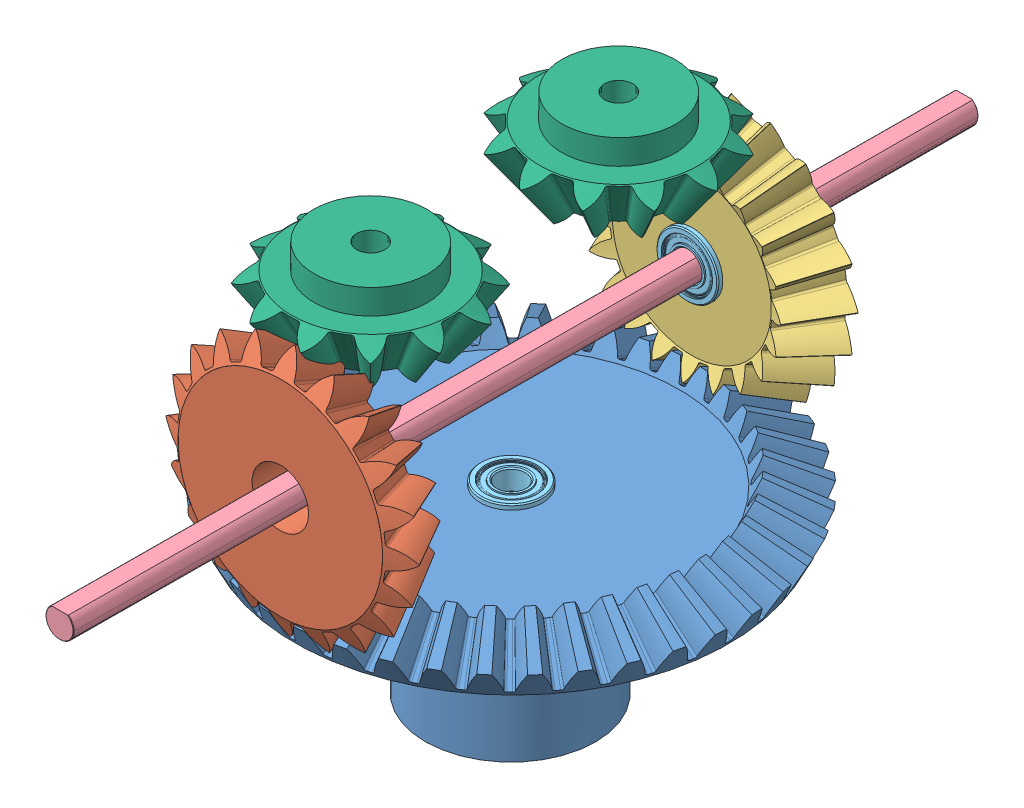
SolidWorks assembly ARMUS-200-000, configuration Default. Lengths in mm.
Overall size (118.35 104.13 203.23).
9 component instances, 6 part files, 21 mates.
Components (placement in the parent):
- ARMUS-200-001-9: ARMUS-200-001 [ARMUS-200-001] x (0 0.999978 -0.006651) z (0.161152 -0.006564 -0.986908) size (45.52 103.08 103.08)
- ARMUS-200-002-1: ARMUS-200-002 [ARMUS-200-002] at (0 30.1556 51.826) x (0 -0.006651 -0.999978) z (-0.715158 -0.698947 0.004649) size (14.5 56.42 56.42)
- straight bevel pinion_ai-2: straight bevel pinion_ai [Inch - Straight bevel pinion 10DP20PT 40GT 20PA 0.5FW ---20O3.0H2.0MD0.5N] at (0 29.4636 -52.2224) x (0 0.006651 0.999978) z (0.702579 0.71159 -0.004733) size (14.5 56.42 56.42)
- ARMUS-200-003.step-1: ARMUS-200-003.step [Default] at (0 29.1339 -101.7959) x (0 -0.999978 0.006651) z (-1 0 0) size (5.71 203.2 6.34)
- ARMUS-200-004.step-1: ARMUS-200-004.step [Default] at (0 3.0335 -0.0202) x (-0.573566 -0.005448 -0.819141) z (0.819159 -0.003815 -0.573553) size (13.87 4.75 13.87)
- ARMUS-200-004.step-2: ARMUS-200-004.step [Default] at (0 29.5168 -44.2216) x (-0.995747 -0.09213 0.000613) z (-0.092132 0.995725 -0.006623) size (13.87 4.75 13.87)
- ARMUS-200-004.step-3: ARMUS-200-004.step [Default] at (0 30.1024 43.8252) x (0.337758 0.941212 -0.00626) z (-0.941233 0.33775 -0.002246) size (13.87 4.75 13.87)
- straight bevel gear_ai-7: straight bevel gear_ai [ARMUS-200-005] at (-4.8298 60.7194 -28.969) x (0 -0.999978 0.006651) z (-0.258 0.006426 0.966124) size (18.93 43.65 43.65)
- straight bevel gear_ai-8: straight bevel gear_ai [ARMUS-200-005] at (-3.8808 60.3841 27.6811) x (0 -0.999978 0.006651) z (-1 0 0) size (18.93 43.65 43.65)
Mates (geometry in assembly coordinates):
- Coincident1: coincident anti-aligned: plane of ARMUS-200-001-9
- Coincident2: coincident: point of ARMUS-200-001-9; point of ARMUS-200-002-1
- Perpendicular1: perpendicular: line of ARMUS-200-001-9 through (0 -9.9998 0.0665) axis (0 0.999978 -0.006651); line of ARMUS-200-002-1 through (0 30.2221 61.8258) axis (0 -0.006651 -0.999978)
- Coincident4: coincident: line of ARMUS-200-002-1 through (0 30.2221 61.8258) axis (0 -0.006651 -0.999978)
- Concentric1: concentric anti-aligned: cylinder of ARMUS-200-002-1 through (0 29.8096 -0.1982) axis (0 0.006651 0.999978) radius 6.35; cylinder of straight bevel pinion_ai-2 through (0 29.8096 -0.1981) axis (0 -0.006651 -0.999978) radius 6.35
- Coincident5: coincident: line of assembly; point of ARMUS-200-002-1; line of straight bevel pinion_ai-2 through (0 29.8096 -0.1982) axis (-0.283557 -0.293279 -0.913008)
- Concentric5: concentric aligned: cylinder of ARMUS-200-002-1 through (0 29.8096 -0.1982) axis (0 0.006651 0.999978) radius 6.35; cylinder of ARMUS-200-004.step-3 through (0 30.0783 40.1931) axis (0 0.006651 0.999978) radius 6.35
- Coincident9: coincident anti-aligned: plane of ARMUS-200-002-1 through (0 30.0783 40.1931) normal (0 -0.006651 -0.999978); plane of ARMUS-200-004.step-3 through (0 30.0783 40.1931) normal (0 0.006651 0.999978)
- Parallel1: parallel anti-aligned: plane of ARMUS-200-001-9 through (0 6.6656 -0.0443) normal (0 0.999978 -0.006651); plane of straight bevel gear_ai-7 through (-4.8298 49.559 -28.8948) normal (0 -0.999978 0.006651)
- Parallel2: parallel anti-aligned: plane of ARMUS-200-001-9 through (0 6.6656 -0.0443) normal (0 0.999978 -0.006651); plane of straight bevel gear_ai-8 through (-3.8808 49.2237 27.7553) normal (0 -0.999978 0.006651)
- Parallel3: parallel aligned: plane of ARMUS-200-001-9 through (0 6.6656 -0.0443) normal (0 0.999978 -0.006651); plane of ARMUS-200-003.step-1 through (1.8935 33.0291 101.3826) normal (0 0.999978 -0.006651)
- Concentric7: concentric anti-aligned: cylinder of straight bevel pinion_ai-2 through (0 29.8096 -0.1981) axis (0 -0.006651 -0.999978) radius 6.35; cylinder of ARMUS-200-004.step-2 through (0 29.5168 -44.2216) axis (0 0.006651 0.999978) radius 3.175
- Coincident14: coincident anti-aligned: plane of straight bevel pinion_ai-2 through (0 29.541 -40.5895) normal (0 0.006651 0.999978); plane of ARMUS-200-004.step-2 through (0 29.541 -40.5895) normal (0 -0.006651 -0.999978)
- Concentric11: concentric aligned: cylinder of ARMUS-200-001-9 through (0 63.4986 -0.4223) axis (0 -0.999978 0.006651) radius 6.35; cylinder of ARMUS-200-004.step-1 through (0 6.6656 -0.0443) axis (0 -0.999978 0.006651) radius 6.35
- Coincident15: coincident anti-aligned: plane of ARMUS-200-001-9 through (0 6.6656 -0.0443) normal (0 0.999978 -0.006651); plane of ARMUS-200-004.step-1 through (0 6.6656 -0.0443) normal (0 -0.999978 0.006651)
- Concentric12: concentric aligned: cylinder of straight bevel pinion_ai-2 through (0 29.8096 -0.1981) axis (0 -0.006651 -0.999978) radius 6.35; cylinder of ARMUS-200-003.step-1 through (0 30.4854 101.3996) axis (0 -0.006651 -0.999978) radius 3.1712
- Coincident18: coincident: unknown of ARMUS-200-001-9
- Width1: width aligned: plane of ARMUS-200-003.step-1 through (0 30.4854 101.3996) normal (0 0.006651 0.999978); plane of ARMUS-200-003.step-1 through (0 29.1339 -101.7959) normal (0 -0.006651 -0.999978); plane of ARMUS-200-002-1 through (0 30.1556 51.8261) normal (0 0.006651 0.999978); plane of straight bevel pinion_ai-2 through (0 29.4636 -52.2225) normal (0 -0.006651 -0.999978)
- GearMate1: gear = 25.4 : 50.8 mm: cylinder of ARMUS-200-001-9 through (0 -33.6891 0.2241) axis (0 0.999978 -0.006651) radius 19.05; cylinder of straight bevel pinion_ai-2 through (0 29.8096 -0.1981) axis (0 -0.006651 -0.999978) radius 6.35
- GearMate2: gear = 25.4 : 50.8 mm: cylinder of ARMUS-200-001-9 through (0 -33.6891 0.2241) axis (0 0.999978 -0.006651) radius 19.05; cylinder of ARMUS-200-002-1 through (0 29.8096 -0.1982) axis (0 0.006651 0.999978) radius 6.35
- GearMate3: gear = 25.4 : 25.4 mm: cylinder of ARMUS-200-002-1 through (0 29.8096 -0.1982) axis (0 0.006651 0.999978) radius 6.35; cylinder of straight bevel pinion_ai-2 through (0 29.8096 -0.1981) axis (0 -0.006651 -0.999978) radius 6.35
